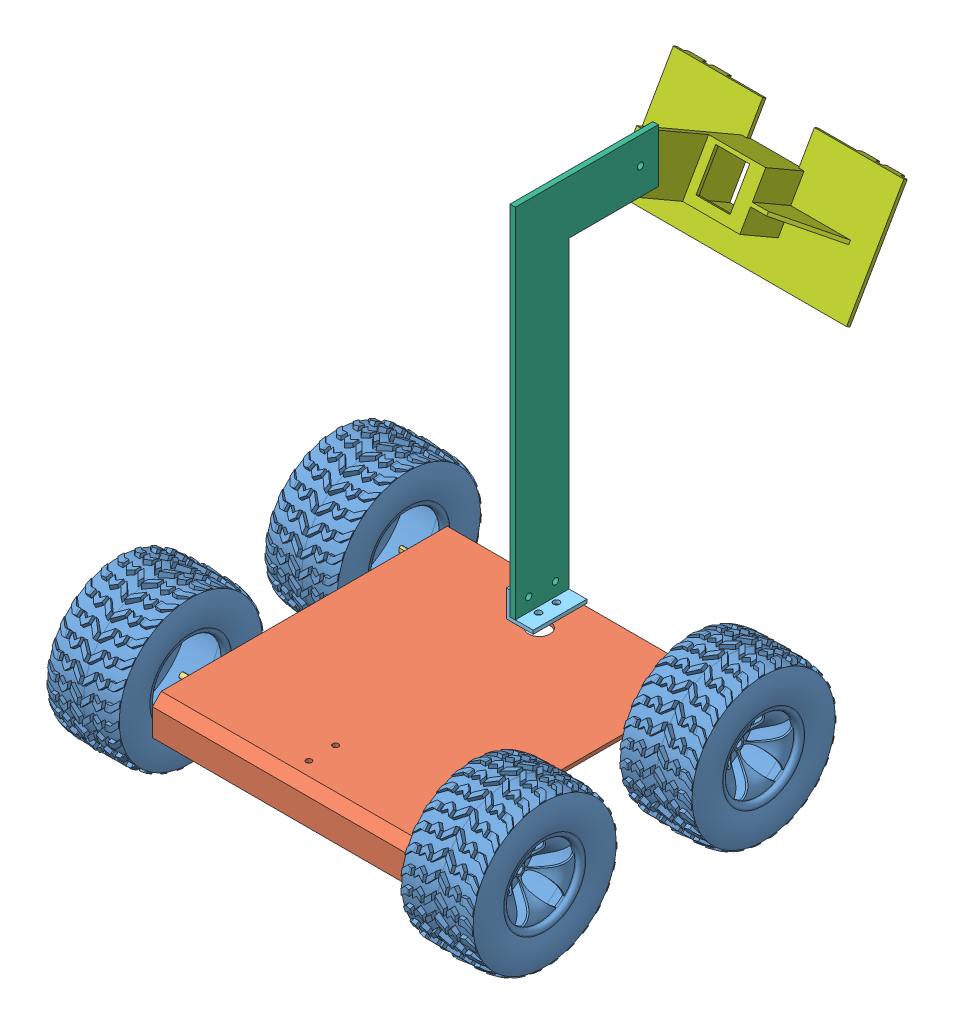
SolidWorks assembly Rover, configuration Default. Lengths in mm.
Overall size (241.47 269.56 297.84).
56 component instances, 20 part files, 8 mates.
Components (placement in the parent):
- Tyre-1: Tyre [Default] at (0 0.8573 7.5165) size (43.08 85.57 85.56)
- Part3^Rover-1: Part3^Rover [Default] at origin (virtual)
- Body-1: Body [Default] at (-173.8741 7.9623 70.6292) x (0 0 -1) z (1 0 0) size (170 20 150)
- Tyre-2: Tyre [Default] at (-0.1024 0.8788 129.9124) size (43.08 85.57 85.56)
- Tyre-3: Tyre [Default] at (-197.8439 0.9353 130.1928) x (-1 0 0) z (0 0 -1) size (43.08 85.57 85.56)
- Tyre-4: Tyre [Default] at (-198.3903 0.9699 7.5973) x (-1 0 0) z (0 0 -1) size (43.08 85.57 85.56)
- Pololu-Micro-Metal-Gearmotor-1: Pololu-Micro-Metal-Gearmotor [По умолчанию] at (-151.1447 0.9502 7.6172) x (0 0 1) z (0 -1 0) size (12.1 35.27 10.12)
- 9d80ad98c65152257df51159fcadeb73-1: 9d80ad98c65152257df51159fcadeb73 [Default] at (-150.7837 5.8733 7.6008) x (0 0 1) z (1 0 0) size (28.57 12.7 24.13)
- Pololu-Micro-Metal-Gearmotor-2: Pololu-Micro-Metal-Gearmotor [По умолчанию] at (-151.2047 0.9752 130.1901) x (0 0 -1) z (0 1 0) size (12.1 35.27 10.12)
- 9d80ad98c65152257df51159fcadeb73-2: 9d80ad98c65152257df51159fcadeb73 [Default] at (-150.7124 5.9997 130.2081) x (0 0 1) z (1 0 0) size (28.57 12.7 24.13)
- Pololu-Micro-Metal-Gearmotor-3: Pololu-Micro-Metal-Gearmotor [По умолчанию] at (-46.4486 0.9209 129.839) x (0 0 -1) z (0 -1 0) size (12.1 35.27 10.12)
- 9d80ad98c65152257df51159fcadeb73-3: 9d80ad98c65152257df51159fcadeb73 [Default] at (-46.837 5.9384 129.8268) x (0 0 -1) z (-1 0 0) size (28.57 12.7 24.13)
- Pololu-Micro-Metal-Gearmotor-4: Pololu-Micro-Metal-Gearmotor [По умолчанию] at (-46.4111 0.8158 7.5383) x (0 0 -1) z (0 -1 0) size (12.1 35.27 10.12)
- 9d80ad98c65152257df51159fcadeb73-4: 9d80ad98c65152257df51159fcadeb73 [Default] at (-46.7953 5.9321 7.5411) x (0 0 -1) z (-1 0 0) size (28.57 12.7 24.13)
- CameraMountLPart-1: CameraMountLPart [Default] at (-109.485 10.9085 -8.0282) size (15 15 30)
- CameraMountArm-1: CameraMountArm [Default] at (-107.4721 12.8701 21.9737) x (0 0 -1) z (1 0 0) size (80 200 3)
- CameraAttachment-1: CameraAttachment [Default] at (-107.4727 154.1118 -99.0424) x (1 0 0) z (0 -0.866025 0.5) size (129 74 64.06)
- CLAW-1: CLAW [Default] at (121.2143 22.0488 23.2928) x (1 0 0) z (0 1 0) size (300 197.14 110) (hidden)
  - adjustmentHingePlate-1: adjustmentHingePlate [Default] at (-171.6086 67.3514 -20.0242) size (50 14 3)
  - adjustmentHingePlate-2: adjustmentHingePlate [Default] at (-171.6086 67.3514 -23.0242) size (50 14 3)
  - adjustmentHingePlate-3: adjustmentHingePlate [Default] at (-319.6086 67.3514 -17.0242) size (50 14 3)
  - adjustmentHingePlate-4: adjustmentHingePlate [Default] at (-319.6086 67.3514 -20.0242) size (50 14 3)
  - adjustmentHingePlate-5: adjustmentHingePlate [Default] at (-319.6086 67.3514 -23.0242) size (50 14 3)
  - adjustmentHingePlate-6: adjustmentHingePlate [Default] at (-171.6086 67.3514 -5.0242) size (50 14 3)
  - adjustmentHingePlate-7: adjustmentHingePlate [Default] at (-171.6086 67.3514 -8.0242) size (50 14 3)
  - adjustmentHingePlate-8: adjustmentHingePlate [Default] at (-171.6086 67.3514 -11.0242) size (50 14 3)
  - adjustmentHingePlate-9: adjustmentHingePlate [Default] at (-319.6086 67.3514 -5.0242) size (50 14 3)
  - adjustmentHingePlate-10: adjustmentHingePlate [Default] at (-319.6086 67.3514 -8.0242) size (50 14 3)
  - adjustmentHingePlate-11: adjustmentHingePlate [Default] at (-171.6086 67.3514 -17.0242) size (50 14 3)
  - adjustmentHingePlate-12: adjustmentHingePlate [Default] at (-319.6086 67.3514 -11.0242) size (50 14 3)
  - plate-1: plate [Default] at (-270.6086 1.3514 -14.0242) size (200 80 3)
  - TOWER PRO MG-995, ANALOG SERVO-1: TOWER PRO MG-995, ANALOG SERVO [Default] at (-255.0724 76.6649 -23.9242) x (0 0 -1) z (0 -1 0) size (19.81 47.29 67)
    - TOWER PRO MG-995, ANALOG SERVO, BODY, BOTTOM-1: TOWER PRO MG-995, ANALOG SERVO, BODY, BOTTOM [Default] at origin size (19.81 6.4 40.61)
    - TOWER PRO MG-995, ANALOG SERVO, BODY, MIDDLE-1: TOWER PRO MG-995, ANALOG SERVO, BODY, MIDDLE [Default] at (0 10.25 0) size (19.8 20.5 40.6)
    - TOWER PRO MG-995, ANALOG SERVO, BODY, TOP-1: TOWER PRO MG-995, ANALOG SERVO, BODY, TOP [Default] at (0 20.5 0) size (19.8 13.2 54.6)
    - TOWER PRO MG-995, ANALOG SERVO, CONNECTOR-1: TOWER PRO MG-995, ANALOG SERVO, CONNECTOR [Default] at (0 -1.3147 -20.3) size (6.8 4.1 19.4)
    - TOWER PRO MG-995, ANALOG SERVO, SHAFT-1: TOWER PRO MG-995, ANALOG SERVO, SHAFT [Default] at (0 20.5 -10.3) x (-0.999988 0 -0.004881) z (0.004881 0 -0.999988) size (5.76 17.5 5.8)
    - TOWER PRO MG-995, ANALOG SERVO, HORN-1: TOWER PRO MG-995, ANALOG SERVO, HORN [Default] at (0 35 -10.3) x (0.999988 0 0.004881) z (-0.004881 0 0.999988) size (12.7 5.75 38.36)
    - pan cross head_am_B18.6.7M - M2 x 0.4 x 10 Type I Cross Recessed PHMS_ --10N-1: pan cross head_am_B18.6.7M - M2 x 0.4 x 10 Type I Cross Recessed PHMS_ --10N [Default] at (-7.7 -6.5 18.1) x (0 1 0) z (0 0 1) size (11.64 4 4.03)
    - pan cross head_am_B18.6.7M - M2 x 0.4 x 10 Type I Cross Recessed PHMS_ --10N-2: pan cross head_am_B18.6.7M - M2 x 0.4 x 10 Type I Cross Recessed PHMS_ --10N [Default] at (7.7 -6.5 18.1) x (0 1 0) z (0 0 1) size (11.64 4 4.03)
    - pan cross head_am_B18.6.7M - M2 x 0.4 x 10 Type I Cross Recessed PHMS_ --10N-3: pan cross head_am_B18.6.7M - M2 x 0.4 x 10 Type I Cross Recessed PHMS_ --10N [Default] at (7.7 -6.5 -18.1) x (0 1 0) z (0 0 1) size (11.64 4 4.03)
    - pan cross head_am_B18.6.7M - M2 x 0.4 x 10 Type I Cross Recessed PHMS_ --10N-4: pan cross head_am_B18.6.7M - M2 x 0.4 x 10 Type I Cross Recessed PHMS_ --10N [Default] at (-7.7 -6.5 -18.1) x (0 1 0) z (0 0 1) size (11.64 4 4.03)
  - TOWER PRO MG-995, ANALOG SERVO-2: TOWER PRO MG-995, ANALOG SERVO [Default] at (-255.0724 76.6649 -1.1242) x (0 0 -1) z (0 -1 0) size (19.81 47.29 67)
    - TOWER PRO MG-995, ANALOG SERVO, BODY, BOTTOM-1: TOWER PRO MG-995, ANALOG SERVO, BODY, BOTTOM [Default] at origin size (19.81 6.4 40.61)
    - TOWER PRO MG-995, ANALOG SERVO, BODY, MIDDLE-1: TOWER PRO MG-995, ANALOG SERVO, BODY, MIDDLE [Default] at (0 10.25 0) size (19.8 20.5 40.6)
    - TOWER PRO MG-995, ANALOG SERVO, BODY, TOP-1: TOWER PRO MG-995, ANALOG SERVO, BODY, TOP [Default] at (0 20.5 0) size (19.8 13.2 54.6)
    - TOWER PRO MG-995, ANALOG SERVO, CONNECTOR-1: TOWER PRO MG-995, ANALOG SERVO, CONNECTOR [Default] at (0 -1.3147 -20.3) size (6.8 4.1 19.4)
    - TOWER PRO MG-995, ANALOG SERVO, SHAFT-1: TOWER PRO MG-995, ANALOG SERVO, SHAFT [Default] at (0 20.5 -10.3) x (-0.999988 0 -0.004881) z (0.004881 0 -0.999988) size (5.76 17.5 5.8)
    - TOWER PRO MG-995, ANALOG SERVO, HORN-1: TOWER PRO MG-995, ANALOG SERVO, HORN [Default] at (0 35 -10.3) x (0.999988 0 0.004881) z (-0.004881 0 0.999988) size (12.7 5.75 38.36)
    - pan cross head_am_B18.6.7M - M2 x 0.4 x 10 Type I Cross Recessed PHMS_ --10N-1: pan cross head_am_B18.6.7M - M2 x 0.4 x 10 Type I Cross Recessed PHMS_ --10N [Default] at (-7.7 -6.5 18.1) x (0 1 0) z (0 0 1) size (11.64 4 4.03)
    - pan cross head_am_B18.6.7M - M2 x 0.4 x 10 Type I Cross Recessed PHMS_ --10N-2: pan cross head_am_B18.6.7M - M2 x 0.4 x 10 Type I Cross Recessed PHMS_ --10N [Default] at (7.7 -6.5 18.1) x (0 1 0) z (0 0 1) size (11.64 4 4.03)
    - pan cross head_am_B18.6.7M - M2 x 0.4 x 10 Type I Cross Recessed PHMS_ --10N-3: pan cross head_am_B18.6.7M - M2 x 0.4 x 10 Type I Cross Recessed PHMS_ --10N [Default] at (7.7 -6.5 -18.1) x (0 1 0) z (0 0 1) size (11.64 4 4.03)
    - pan cross head_am_B18.6.7M - M2 x 0.4 x 10 Type I Cross Recessed PHMS_ --10N-4: pan cross head_am_B18.6.7M - M2 x 0.4 x 10 Type I Cross Recessed PHMS_ --10N [Default] at (-7.7 -6.5 -18.1) x (0 1 0) z (0 0 1) size (11.64 4 4.03)
  - lowerClaw-1: lowerClaw [Default] at (-371.9616 143.4939 -65.6122) x (0 1 0) z (1 0 0) size (54.93 52.35 300)
  - upperClaw-1: upperClaw [Default] at (-371.9616 143.4939 -65.6122) x (0 1 0) z (1 0 0) size (109.92 110 300)
- HexKeyPart-3.0mm-1: HexKeyPart-3.0mm [Default] at (-22.2773 0.8602 130.1099) x (-0.004564 0.0248 -0.999682) z (0.999989 -0.001026 -0.004591) size (7.15 8.08 17)
Mates (geometry in assembly coordinates):
- Lock5: lock: unknown of Pololu-Micro-Metal-Gearmotor-1; unknown of 9d80ad98c65152257df51159fcadeb73-1
- Lock6: lock: unknown of Tyre-4; unknown of Pololu-Micro-Metal-Gearmotor-1
- Lock7: lock: unknown of Tyre-3; unknown of Pololu-Micro-Metal-Gearmotor-2
- Lock8: lock: unknown of Pololu-Micro-Metal-Gearmotor-2; unknown of 9d80ad98c65152257df51159fcadeb73-2
- Lock9: lock: unknown of Pololu-Micro-Metal-Gearmotor-3; unknown of 9d80ad98c65152257df51159fcadeb73-3
- Lock10: lock: unknown of Tyre-2; unknown of Pololu-Micro-Metal-Gearmotor-3
- Lock11: lock: unknown of Pololu-Micro-Metal-Gearmotor-4; unknown of 9d80ad98c65152257df51159fcadeb73-4
- Lock12: lock: unknown of Tyre-1; unknown of Pololu-Micro-Metal-Gearmotor-4
